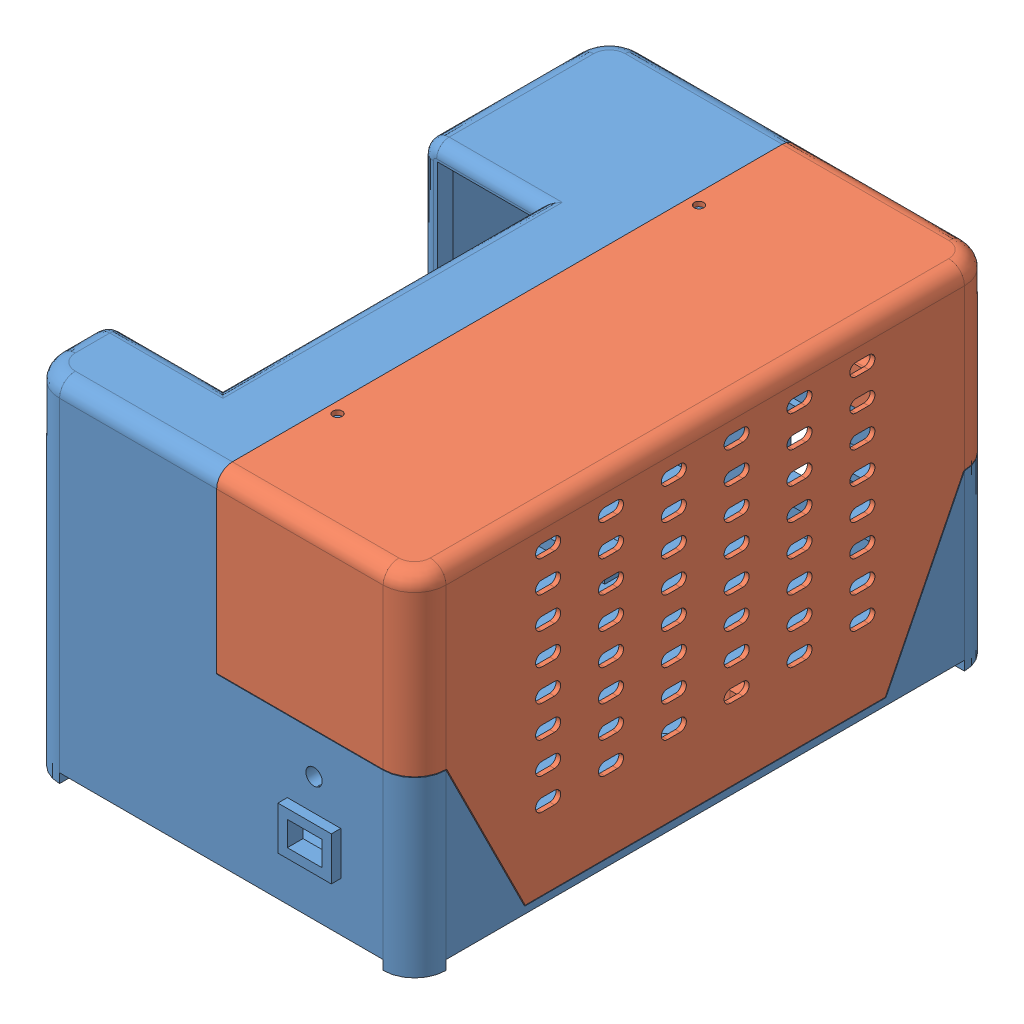
SolidWorks assembly Modelo Caja, configuration Predeterminado. Lengths in mm.
Overall size (123 111.2 192).
3 component instances, 3 part files, 5 mates.
Components (placement in the parent):
- chassis_A-1: chassis_A [Predeterminado] at (-94.0358 -47.3495 272.5) size (123 111.2 192)
- Bus-1: Bus [Predeterminado] at (-4.3395 -21.7096 98.4774) x (-1 0 0) z (0 0 -1) size (26.55 11.3 16.5) (hidden)
- chassis_B-1: chassis_B [Predeterminado] at origin size (63 105.8 185)
Mates (geometry in assembly coordinates):
- Distancia2: distance = 15 mm: plane of Pieza1-1 through (8.9642 -17.5495 86.4774) normal (1 0 0); plane of chassis_A-1 through (23.9642 -45.1495 267.5) normal (1 0 0)
- Distancia3: distance = 20 mm: plane of Pieza1-1 through (-16.0858 -27.3495 86.4774) normal (0 -1 0); plane of chassis_A-1 through (13.9642 -47.3495 102.5) normal (0 -1 0)
- Coincidente1: coincident anti-aligned: plane of chassis_A-1 through (-94.0358 -41.1495 272.5) normal (0 1 0); plane of ciluetaf-1 through (-93.0358 -41.1495 112.2) normal (0 -1 0)
- Paralelo1: parallel aligned: plane of chassis_A-1 through (-89.0358 -45.1495 277.5) normal (0 0 1); plane of ciluetaf-1 through (-93.0358 -41.1495 272.2) normal (0 0 1)
- Concéntrica1: concentric aligned: circle of caja-1; circle of ciluetaf-1
